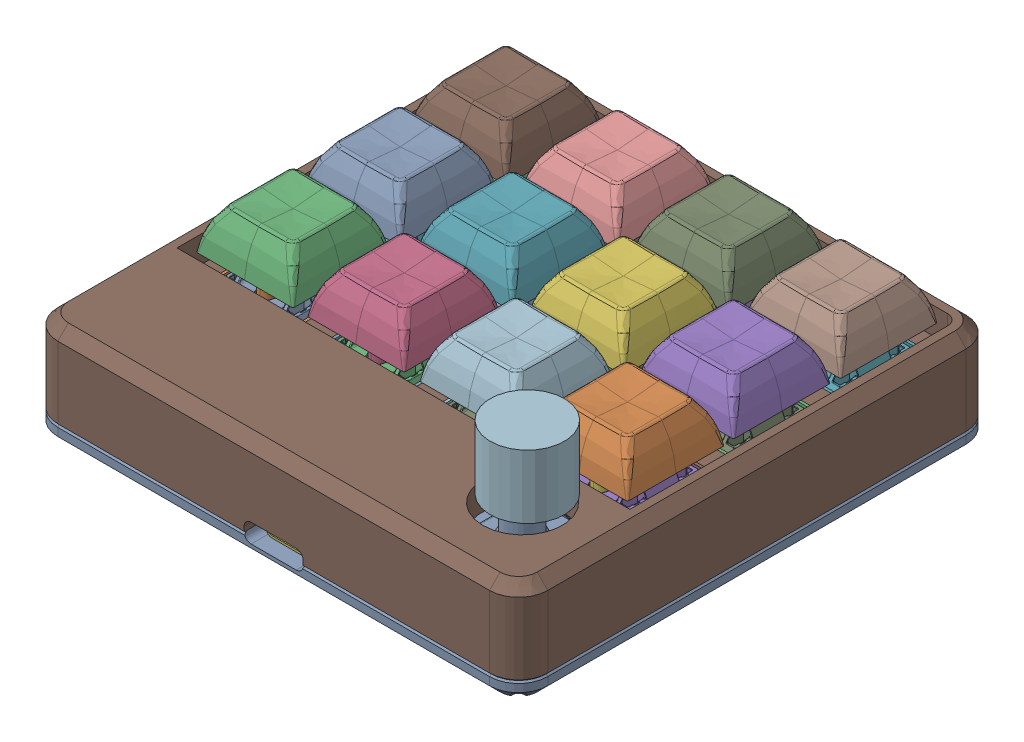
SolidWorks assembly PCBCase Assembly, configuration Default. Lengths in mm.
Overall size (92.5 33.56 90).
16 component instances, 5 part files, 43 mates.
Components (placement in the parent):
- Base-1: Base [Default] at (-28.481 -4.6295 15.4567) size (92.5 7.65 90)
- PCB-1: PCB [Default] at (14.272 3.282 -26.0294) x (-1 0 -0.000653) z (0 1 0) size (85.01 83.9 25.41)
- Cover-1: Cover [Default] at (-28.481 14.9591 15.4567) x (1 0 0) z (0 0 -1) size (92.5 16 90)
- DSA_Keycap_CherryMX-1: DSA_Keycap_CherryMX [Default] at (-17.9854 14.3705 25.1236) x (1 0 0.000653) z (-0.000653 0 1) size (18.33 7.74 18.35)
- DSA_Keycap_CherryMX-2: DSA_Keycap_CherryMX [Default] at (-60.1722 14.3705 4.896) x (1 0 0.000653) z (-0.000653 0 1) size (18.33 7.74 18.35)
- DSA_Keycap_CherryMX-3: DSA_Keycap_CherryMX [Default] at (3.0146 14.3705 25.1373) x (1 0 0.000653) z (-0.000653 0 1) size (18.33 7.74 18.35)
- DSA_Keycap_CherryMX-4: DSA_Keycap_CherryMX [Default] at (-60.1854 14.3705 25.096) x (1 0 0.000653) z (-0.000653 0 1) size (18.33 7.74 18.35)
- DSA_Keycap_CherryMX-5: DSA_Keycap_CherryMX [Default] at (-39.1854 14.3705 25.1097) x (1 0 0.000653) z (-0.000653 0 1) size (18.33 7.74 18.35)
- DSA_Keycap_CherryMX-6: DSA_Keycap_CherryMX [Default] at (2.8278 14.3705 4.9372) x (1 0 0.000653) z (-0.000653 0 1) size (18.33 7.74 18.35)
- DSA_Keycap_CherryMX-7: DSA_Keycap_CherryMX [Default] at (-17.9722 14.3705 4.9236) x (1 0 0.000653) z (-0.000653 0 1) size (18.33 7.74 18.35)
- DSA_Keycap_CherryMX-8: DSA_Keycap_CherryMX [Default] at (-38.9722 14.3705 4.9099) x (1 0 0.000653) z (-0.000653 0 1) size (18.33 7.74 18.35)
- DSA_Keycap_CherryMX-9: DSA_Keycap_CherryMX [Default] at (3.0409 14.3705 -15.0627) x (1 0 0.000653) z (-0.000653 0 1) size (18.33 7.74 18.35)
- DSA_Keycap_CherryMX-10: DSA_Keycap_CherryMX [Default] at (-18.1591 14.3705 -15.0765) x (1 0 0.000653) z (-0.000653 0 1) size (18.33 7.74 18.35)
- DSA_Keycap_CherryMX-11: DSA_Keycap_CherryMX [Default] at (-39.1591 14.3705 -15.0903) x (1 0 0.000653) z (-0.000653 0 1) size (18.33 7.74 18.35)
- DSA_Keycap_CherryMX-12: DSA_Keycap_CherryMX [Default] at (-60.1591 14.3705 -15.104) x (1 0 0.000653) z (-0.000653 0 1) size (18.33 7.74 18.35)
- Knob-2: Knob [Default] at (3.7902 16.782 44.8404) x (0.319081 0 0.947727) z (-0.947727 0 0.319081) size (14 12 14)
Mates (geometry in assembly coordinates):
- Coincident10: coincident aligned: plane of Base-1 through (17.7698 -0.6295 54.9567) normal (1 0 0); plane of Cover-1 through (17.7698 -1.0409 -24.0433) normal (1 0 0)
- Coincident11: coincident aligned: plane of Base-1 through (12.269 -0.6295 -29.5441) normal (0 0 -1); plane of Cover-1 through (-69.231 -1.0409 -29.5441) normal (0 0 -1)
- Concentric1: concentric aligned: cylinder of Base-1 through (-8.2302 2.8705 -22.5441) axis (0 -1 0) radius 1.1; cylinder of PCB-1 through (-8.2302 2.8705 -22.5441) axis (0 -1 0) radius 1.1
- Parallel1: parallel aligned: cylinder of Base-1 through (-48.7317 2.8705 -22.5441) axis (0 -1 0) radius 1.1; cylinder of PCB-1 through (-48.7302 2.8705 -22.5705) axis (0 -1 0) radius 1.1
- Coincident13: coincident anti-aligned: plane of PCB-1 through (2.9147 18.2705 25.0372) normal (0 1 0); plane of DSA_Keycap_CherryMX-2 through (-60.1722 18.2705 4.896) normal (0 -1 0)
- Coincident14: coincident anti-aligned: plane of Base-1 through (-8.2302 2.8705 -22.5441) normal (0 1 0); plane of PCB-1 through (14.2707 2.8705 -24.0294) normal (0 -1 0)
- Coincident16: coincident anti-aligned: plane of PCB-1 through (2.9147 18.2705 25.0372) normal (0 1 0); plane of DSA_Keycap_CherryMX-3 through (3.0146 18.2705 25.1373) normal (0 -1 0)
- Coincident19: coincident anti-aligned: plane of PCB-1 through (-18.0853 18.2705 25.0235) normal (0 1 0); plane of DSA_Keycap_CherryMX-1 through (-17.9854 18.2705 25.1236) normal (0 -1 0)
- Coincident20: coincident anti-aligned: plane of PCB-1 through (-17.534 18.2705 23.0239) normal (0.000653 0 -1); plane of DSA_Keycap_CherryMX-1 through (-17.434 20.7705 23.0239) normal (-0.000653 0 1)
- Coincident21: coincident anti-aligned: plane of PCB-1 through (-20.0857 18.2705 25.6722) normal (-1 0 -0.000653); plane of DSA_Keycap_CherryMX-1 through (-20.085 20.7705 24.5722) normal (1 0 0.000653)
- Coincident22: coincident anti-aligned: plane of PCB-1 through (0.9142 18.2705 25.6859) normal (-1 0 -0.000653); plane of DSA_Keycap_CherryMX-3 through (0.915 20.7705 24.5859) normal (1 0 0.000653)
- Coincident23: coincident anti-aligned: plane of PCB-1 through (3.466 18.2705 23.0376) normal (0.000653 0 -1); plane of DSA_Keycap_CherryMX-3 through (3.566 20.7705 23.0377) normal (-0.000653 0 1)
- Coincident24: coincident anti-aligned: plane of PCB-1 through (-39.0853 18.2705 25.0098) normal (0 1 0); plane of DSA_Keycap_CherryMX-5 through (-39.1854 18.2705 25.1097) normal (0 -1 0)
- Coincident25: coincident anti-aligned: plane of PCB-1 through (-38.534 18.2705 23.0102) normal (0.000653 0 -1); plane of DSA_Keycap_CherryMX-5 through (-38.634 20.7705 23.0101) normal (-0.000653 0 1)
- Coincident26: coincident anti-aligned: plane of PCB-1 through (-37.0857 18.2705 25.6611) normal (1 0 0.000653); plane of DSA_Keycap_CherryMX-5 through (-37.0857 20.7705 25.6611) normal (-1 0 -0.000653)
- Coincident27: coincident anti-aligned: plane of PCB-1 through (-60.0853 18.2705 24.9961) normal (0 1 0); plane of DSA_Keycap_CherryMX-4 through (-60.1854 18.2705 25.096) normal (0 -1 0)
- Coincident28: coincident anti-aligned: plane of PCB-1 through (-59.534 18.2705 22.9964) normal (0.000653 0 -1); plane of DSA_Keycap_CherryMX-4 through (-59.634 20.7705 22.9964) normal (-0.000653 0 1)
- Coincident29: coincident anti-aligned: plane of PCB-1 through (-58.0857 18.2705 25.6474) normal (1 0 0.000653); plane of DSA_Keycap_CherryMX-4 through (-58.0857 20.7705 25.6474) normal (-1 0 -0.000653)
- Coincident31: coincident anti-aligned: plane of PCB-1 through (-60.0722 18.2705 4.9961) normal (0 1 0); plane of DSA_Keycap_CherryMX-2 through (-60.1722 18.2705 4.896) normal (0 -1 0)
- Coincident32: coincident anti-aligned: plane of PCB-1 through (-58.0727 18.2705 5.6474) normal (1 0 0.000653); plane of DSA_Keycap_CherryMX-2 through (-58.0725 20.7705 5.4474) normal (-1 0 -0.000653)
- Coincident33: coincident anti-aligned: plane of PCB-1 through (-59.5236 18.2705 6.9964) normal (-0.000653 0 1); plane of DSA_Keycap_CherryMX-2 through (-60.7236 20.7705 6.9957) normal (0.000653 0 -1)
- Coincident34: coincident anti-aligned: plane of PCB-1 through (-38.5236 18.2705 7.0102) normal (-0.000653 0 1); plane of DSA_Keycap_CherryMX-8 through (-39.5236 20.7705 7.0095) normal (0.000653 0 -1)
- Coincident36: coincident anti-aligned: plane of PCB-1 through (-41.0727 18.2705 5.6585) normal (-1 0 -0.000653); plane of DSA_Keycap_CherryMX-8 through (-41.0718 20.7705 4.3585) normal (1 0 0.000653)
- Coincident37: coincident anti-aligned: plane of PCB-1 through (-39.0723 18.2705 5.0098) normal (0 1 0); plane of DSA_Keycap_CherryMX-8 through (-38.9722 18.2705 4.9099) normal (0 -1 0)
- Coincident38: coincident anti-aligned: plane of PCB-1 through (-18.0723 18.2705 5.0235) normal (0 1 0); plane of DSA_Keycap_CherryMX-7 through (-17.9722 18.2705 4.9236) normal (0 -1 0)
- Coincident39: coincident anti-aligned: plane of PCB-1 through (-17.5236 18.2705 7.0239) normal (-0.000653 0 1); plane of DSA_Keycap_CherryMX-7 through (-18.5236 20.7705 7.0232) normal (0.000653 0 -1)
- Coincident40: coincident anti-aligned: plane of PCB-1 through (-20.0727 18.2705 5.6722) normal (-1 0 -0.000653); plane of DSA_Keycap_CherryMX-7 through (-20.0718 20.7705 4.3722) normal (1 0 0.000653)
- Coincident42: coincident anti-aligned: plane of PCB-1 through (2.9277 18.2705 5.0372) normal (0 1 0); plane of DSA_Keycap_CherryMX-6 through (2.8278 18.2705 4.9372) normal (0 -1 0)
- Coincident44: coincident anti-aligned: plane of PCB-1 through (4.9273 18.2705 5.6885) normal (1 0 0.000653); plane of DSA_Keycap_CherryMX-6 through (4.9274 20.7705 5.4885) normal (-1 0 -0.000653)
- Coincident45: coincident anti-aligned: plane of PCB-1 through (3.4764 18.2705 7.0376) normal (-0.000653 0 1); plane of DSA_Keycap_CherryMX-6 through (2.2764 20.7705 7.0368) normal (0.000653 0 -1)
- Coincident46: coincident anti-aligned: plane of PCB-1 through (2.9408 18.2705 -14.9628) normal (0 1 0); plane of DSA_Keycap_CherryMX-9 through (3.0409 18.2705 -15.0627) normal (0 -1 0)
- Coincident47: coincident anti-aligned: plane of PCB-1 through (0.9404 18.2705 -14.3141) normal (-1 0 -0.000653); plane of DSA_Keycap_CherryMX-9 through (0.9412 20.7705 -15.6141) normal (1 0 0.000653)
- Coincident48: coincident anti-aligned: plane of PCB-1 through (3.4895 18.2705 -12.9624) normal (-0.000653 0 1); plane of DSA_Keycap_CherryMX-9 through (2.4895 20.7705 -12.9631) normal (0.000653 0 -1)
- Coincident49: coincident anti-aligned: plane of PCB-1 through (-18.0592 18.2705 -14.9765) normal (0 1 0); plane of DSA_Keycap_CherryMX-10 through (-18.1591 18.2705 -15.0765) normal (0 -1 0)
- Coincident50: coincident anti-aligned: plane of PCB-1 through (-17.5105 18.2705 -12.9761) normal (-0.000653 0 1); plane of DSA_Keycap_CherryMX-10 through (-18.7105 20.7705 -12.9769) normal (0.000653 0 -1)
- Coincident51: coincident anti-aligned: plane of PCB-1 through (-16.0596 18.2705 -14.3252) normal (1 0 0.000653); plane of DSA_Keycap_CherryMX-10 through (-16.0595 20.7705 -14.5252) normal (-1 0 -0.000653)
- Coincident52: coincident anti-aligned: plane of PCB-1 through (-39.0592 18.2705 -14.9902) normal (0 1 0); plane of DSA_Keycap_CherryMX-11 through (-39.1591 18.2705 -15.0903) normal (0 -1 0)
- Coincident53: coincident anti-aligned: plane of PCB-1 through (-38.5105 18.2705 -12.9898) normal (-0.000653 0 1); plane of DSA_Keycap_CherryMX-11 through (-39.7105 20.7705 -12.9906) normal (0.000653 0 -1)
- Coincident54: coincident anti-aligned: plane of PCB-1 through (-37.0596 18.2705 -14.3389) normal (1 0 0.000653); plane of DSA_Keycap_CherryMX-11 through (-37.0595 20.7705 -14.5389) normal (-1 0 -0.000653)
- Coincident55: coincident anti-aligned: plane of PCB-1 through (-60.0592 18.2705 -15.0039) normal (0 1 0); plane of DSA_Keycap_CherryMX-12 through (-60.1591 18.2705 -15.104) normal (0 -1 0)
- Coincident56: coincident anti-aligned: plane of PCB-1 through (-58.0596 18.2705 -14.3526) normal (1 0 0.000653); plane of DSA_Keycap_CherryMX-12 through (-58.0595 20.7705 -14.5526) normal (-1 0 -0.000653)
- Coincident57: coincident anti-aligned: plane of PCB-1 through (-59.5105 18.2705 -13.0036) normal (-0.000653 0 1); plane of DSA_Keycap_CherryMX-12 through (-60.7105 20.7705 -13.0043) normal (0.000653 0 -1)
- Coincident59: coincident anti-aligned: plane of PCB-1 through (2.9715 23.782 44.9813) normal (0 1 0); plane of Knob-2 through (3.7902 23.782 44.8404) normal (0 -1 0)
